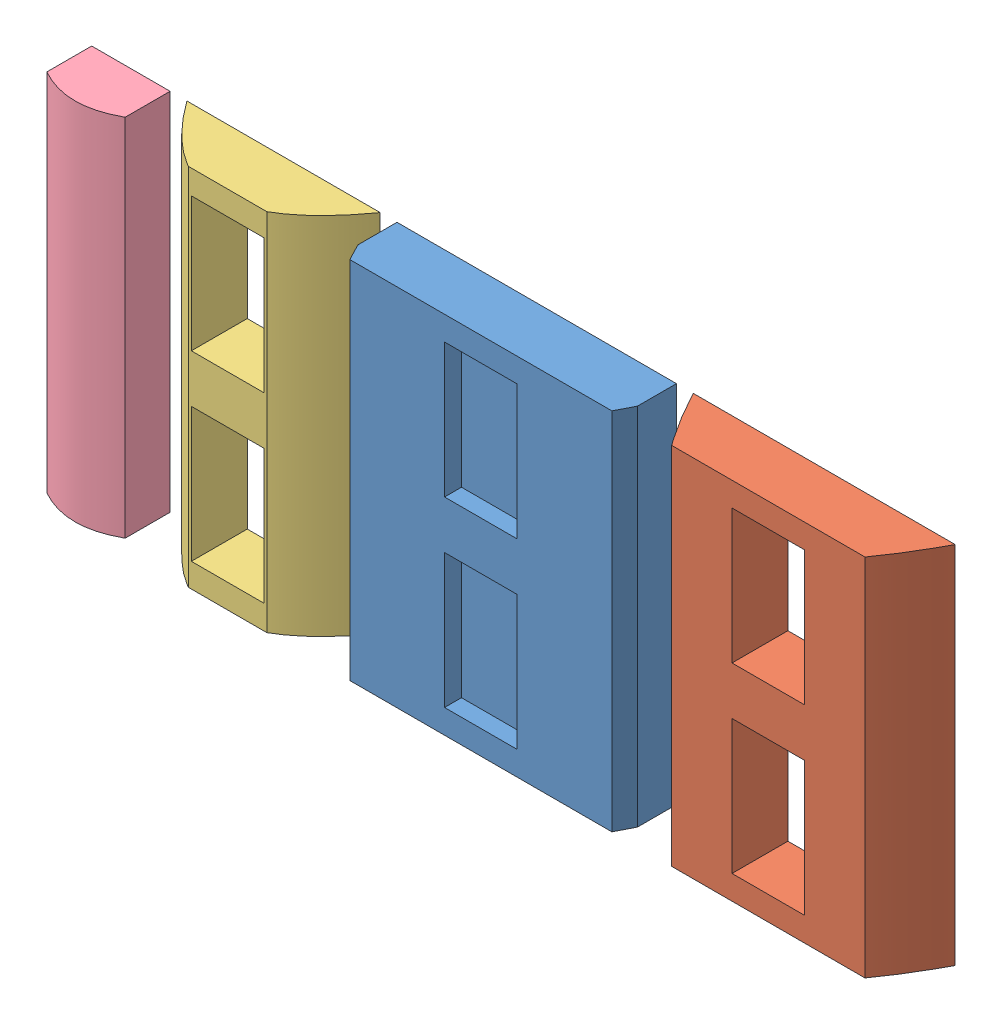
SolidWorks assembly Assem1, configuration Default. Lengths in mm.
Overall size (784.84 331.38 50.8).
4 component instances, 4 part files, 12 mates.
Components (placement in the parent):
- section1-1: section1 [Default] at (0 -331.382 162.4) x (1 0 0) z (0 1 0) size (254 50.8 331.38)
- section2-1: section2 [Default] at (261.2912 -331.382 111.6) x (1 0 0) z (0 1 0) size (238.1 50.8 331.38)
- section3-1: section3 [Default] at (-230.1126 -331.382 60.8) x (1 0 0) z (0 1 0) size (175.75 50.8 331.38)
- section4-1: section4 [Default] at (-368.8623 -331.382 50.8) x (1 0 0) z (0 1 0) size (71.27 50.8 331.38)
Mates (geometry in assembly coordinates):
- Coincident1: coincident anti-aligned: plane of section1-1 through (-116.3498 -331.382 0) normal (0 0 -1); plane of assembly through (0 0 0) normal (0 0 1)
- Coincident2: coincident anti-aligned: plane of section3-1 through (-349.4625 -331.382 0) normal (0 0 -1); plane of assembly through (0 0 0) normal (0 0 1)
- Coincident3: coincident anti-aligned: plane of section4-1 through (-393.8492 -331.382 0) normal (0 0 -1); plane of assembly through (0 0 0) normal (0 0 1)
- Coincident4: coincident anti-aligned: plane of section2-1 through (141.9414 -331.382 0) normal (0 0 -1); plane of assembly through (0 0 0) normal (0 0 1)
- Coincident5: coincident aligned: plane of section2-1 through (271.9414 0 111.6) normal (0 1 0); plane of assembly through (0 0 0) normal (0 1 0)
- Coincident6: coincident aligned: plane of section1-1 through (10.6502 0 162.4) normal (0 1 0); plane of assembly through (0 0 0) normal (0 1 0)
- Coincident7: coincident aligned: plane of section3-1 through (-219.4625 0 60.8) normal (0 1 0); plane of assembly through (0 0 0) normal (0 1 0)
- Coincident8: coincident aligned: plane of section4-1 through (-358.2121 0 50.8) normal (0 1 0); plane of assembly through (0 0 0) normal (0 1 0)
- Distance1: distance = 15.24 mm: line of section2-1 through (142.24 0 0) axis (0 -1 0); plane of section1-1 through (127 -331.382 35.4) normal (1 0 0)
- Distance2: distance = 15.24 mm: line of section3-1 through (-142.24 -331.382 0) axis (0 1 0); plane of section1-1 through (-127 -331.382 35.4) normal (-1 0 0)
- Distance3: distance = 15.24 mm: line of section3-1 through (-317.9853 0 0) axis (0 -1 0); plane of section4-1 through (-333.2253 -331.382 40.8) normal (1 0 0)
- Coincident12: coincident aligned: plane of section1-1; plane of assembly
